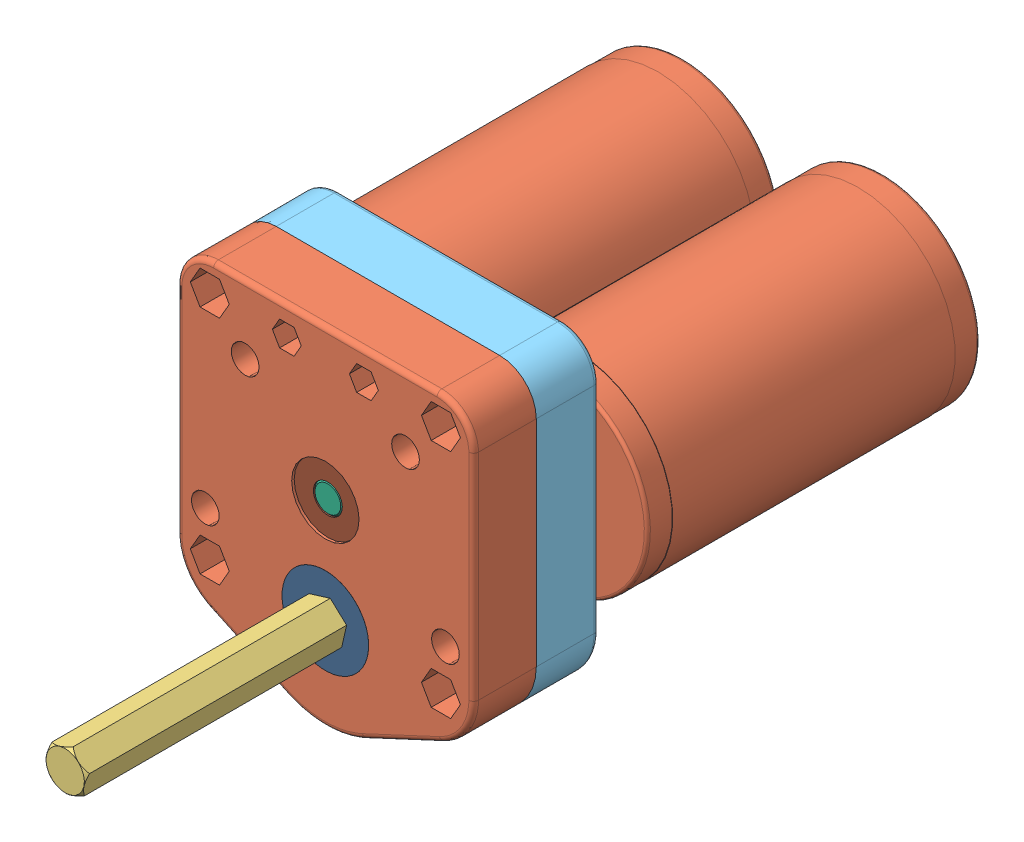
SolidWorks assembly Single Speed, Double Reduction Gearbox 217-2454, configuration Default. Lengths in mm.
Overall size (144.4 117.32 241.64).
41 component instances, 26 part files, 0 mates.
Components (placement in the parent):
- 217-2614-001_12t-1: 217-2614-001_12t [Default] at (33.0031 2.4812 -3.5711) x (0.965926 0.258819 0) z (0 0 -1) size (18.29 18.29 19)
- 217-2614-001_12t-2: 217-2614-001_12t [Default] at (-33.0031 2.4812 -3.5711) x (-0.965926 0.258819 0) z (0 0 -1) size (18.29 18.29 19)
- 217-2454-001 Rev1-1: 217-2454-001 Rev1 [Default] at (0 0 20.6375) x (-1 0 0) z (0 0 -1) size (97.79 114.27 23.82)
- 217-2454-004 Rev1-1: 217-2454-004 Rev1 [Default] at (0 -34.3662 42.9006) x (0 0 1) z (0.733406 -0.679791 0) size (140.21 12.7 16.13)
- 217-2617-004 Rev1_97431A340-1: 217-2617-004 Rev1_97431A340 [Default] at (0 -34.3662 -0.4699) x (0 0 -1) z (0.204366 0.978895 0) size (1.07 20.32 18.5)
- 217-2454-002 Rev1-1: 217-2454-002 Rev1 [Default] at (0 0 -20.6375) size (97.79 114.27 24.07)
- 217-2454-003 Rev1-1: 217-2454-003 Rev1 [Default] x (-0.376207 -0.926535 0) z (0 0 1) size (11 9.53 39.62)
- 217-2731-1: 217-2731 [Default] at (0 -34.3662 -20.6502) x (-0.088591 -0.996068 0) z (-0.996068 0.088591 0) size (31.12 7.94 31.12)
- 217-2707-001_40t-1: 217-2707-001_40t [Default] at (0 0 -6.35) x (-0.137462 0.990507 0) z (0 0 1) size (53.62 53.62 12.65)
- 217-2708-001_40t-1: 217-2708-001_40t [Default] at (0 -34.3662 6.3881) x (0.295252 -0.955419 0) z (0 0 1) size (53.62 53.62 12.65)
- 217-2734-1: 217-2734 [Default] at (0 -34.3662 20.6502) x (-0.955419 -0.295252 0) z (0.295252 -0.955419 0) size (31.12 7.94 31.12)
- 217-2733-1: 217-2733 [Default] at (0 0 12.7) x (0 0 1) z (-0.962149 0.272524 0) size (7.11 24.61 24.61)
- 217-2733-2: 217-2733 [Default] at (0 0 -12.7) x (0 0 -1) z (0.923728 0.383049 0) size (7.11 24.61 24.61)
- Grahill Encoder-1: Grahill Encoder [Default] at (0 -34.3662 -55.8673) x (0.214062 0.97682 0) z (-0.97682 0.214062 0) size (31.75 31.12 31.75)
- 217-2428-019 Rev1-1: 217-2428-019 Rev1 [Default] at (0 -34.3662 -60.3123) size (50.8 19.05 1.57)
- SCREW-832-0375-1: SCREW-832-0375 [Default] at (20.6375 -37.3791 -62.5221) x (0 0 1) z (-0.864968 0.501827 0) size (11.73 7.92 7.92)
- 217-2703-001_24t-1: 217-2703-001_24t [Default] at (0 0 6.35) x (0.731477 -0.681866 0) z (0 0 1) size (33.29 33.29 12.65)
- SCREW-832-0375-2: SCREW-832-0375 [Default] at (20.6375 -37.3791 -15.8877) x (0 0 -1) z (0.606771 0.794877 0) size (11.73 7.92 7.92)
- 832-1250-1: 832-1250 [Default] at (12.7 40.0478 13.9573) x (0 0 -1) z (0.528998 -0.848623 0) size (33.96 7.92 7.92)
- NUT-832-NYLOCK-1: NUT-832-NYLOCK [Default] at (12.7 40.0478 -12.7038) x (1 0 0) z (0 1 0) size (10.2 5.86 8.12)
- 832-1250-2: 832-1250 [Default] at (-12.7 40.0478 13.9573) x (0 0 -1) z (0.969036 -0.246918 0) size (33.96 7.92 7.92)
- NUT-832-NYLOCK-2: NUT-832-NYLOCK [Default] at (-12.7 40.0478 -12.7038) x (1 0 0) z (0 1 0) size (10.2 5.86 8.12)
- SCREW-832-0375-3: SCREW-832-0375 [Default] at (-20.6375 -37.3791 -15.8877) x (0 0 -1) z (-0.99945 -0.033162 0) size (11.73 7.92 7.92)
- SCREW-832-0375-4: SCREW-832-0375 [Default] at (-20.6375 -37.3791 -62.5221) x (0 0 1) z (-0.864968 0.501827 0) size (11.73 7.92 7.92)
- 217-2428-005 Rev1-1: 217-2428-005 Rev1 [Default] at (20.6375 -37.3791 -39.6875) x (0.866025 -0.5 0) z (0.5 0.866025 0) size (7.33 38.98 6.35)
- 217-2428-005 Rev1-2: 217-2428-005 Rev1 [Default] at (-20.6375 -37.3791 -39.6875) x (0.866025 -0.5 0) z (0.5 0.866025 0) size (7.33 38.98 6.35)
- NNYXXXX-ZZ_NNY2520-ZC-1: NNYXXXX-ZZ_NNY2520-ZC [Default] at (38.1 40.0478 -11.7475) x (0.923728 0.383049 0) z (0 0 -1) size (10.96 13.76 7.8)
- NNYXXXX-ZZ_NNY2520-ZC-2: NNYXXXX-ZZ_NNY2520-ZC [Default] at (38.1 -36.1522 -11.7475) x (0.923728 0.383049 0) z (0 0 -1) size (10.96 13.76 7.8)
- 217-2000-1: 217-2000 [Default] at (-33.0031 2.4812 -20.6375) x (0 0 -1) z (0.965926 -0.258819 0) size (150.2 64.01 64.01)
- 217-2000-2: 217-2000 [Default] at (33.0031 2.4812 -20.6375) x (0 0 -1) z (-0.965926 -0.258819 0) size (150.2 64.01 64.01)
- SBS1_SBS1032-0500ZC-1: SBS1_SBS1032-0500ZC [Default] at (-26.4291 27.0157 -15.5321) x (0 0 -1) z (1 0 0) size (15.78 9.29 9.24)
- SBS1_SBS1032-0500ZC-2: SBS1_SBS1032-0500ZC [Default] at (-39.5771 -22.0533 -15.5321) x (0 0 -1) z (1 0 0) size (15.78 9.29 9.24)
- SBS1_SBS1032-0500ZC-3: SBS1_SBS1032-0500ZC [Default] at (26.4291 27.0157 -15.5321) x (0 0 -1) z (1 0 0) size (15.78 9.29 9.24)
- SBS1_SBS1032-0500ZC-4: SBS1_SBS1032-0500ZC [Default] at (39.5771 -22.0533 -15.5321) x (0 0 -1) z (1 0 0) size (15.78 9.29 9.24)
- 217-2614-002_98430A132-1: 217-2614-002_98430A132 [Default] at (33.0031 2.4812 -11.6375) x (0 0 1) z (-1 0 0) size (1.2 14.83 14.83)
- 217-2614-002_98430A132-2: 217-2614-002_98430A132 [Default] at (33.0031 2.4812 5.9285) x (0 0 1) z (-0.37146 0.928449 0) size (1.2 14.83 14.83)
- Grayhill Nut-1: Grayhill Nut [Default] at (0 -34.3662 -56.7309) size (18.33 15.88 2.54)
- Grayhill Lock Washer-1: Grayhill Lock Washer [Default] at (0 -34.3662 -58.3692) x (-0.923728 -0.383049 0) z (0 0 -1) size (19.69 19.69 0.74)
- 217-2761-001 rev1-1: 217-2761-001 rev1 [Default] at (-32.0195 6.1517 -3.0375) x (-0.965926 0.258819 0) z (0 0 1) size (2 2 20)
- 217-2614-002_98430A132-3: 217-2614-002_98430A132 [Default] at (-33.0031 2.4812 -14.1375) x (0 0 1) z (-1 0 0) size (1.2 14.83 14.83)
- 217-3416-001 Rev1_13t Steel Pinion-1: 217-3416-001 Rev1_13t Steel Pinion [Default] at (0 0 1.6506) x (0.794488 0.60728 0) z (0 0 1) size (20.68 20.86 19)
